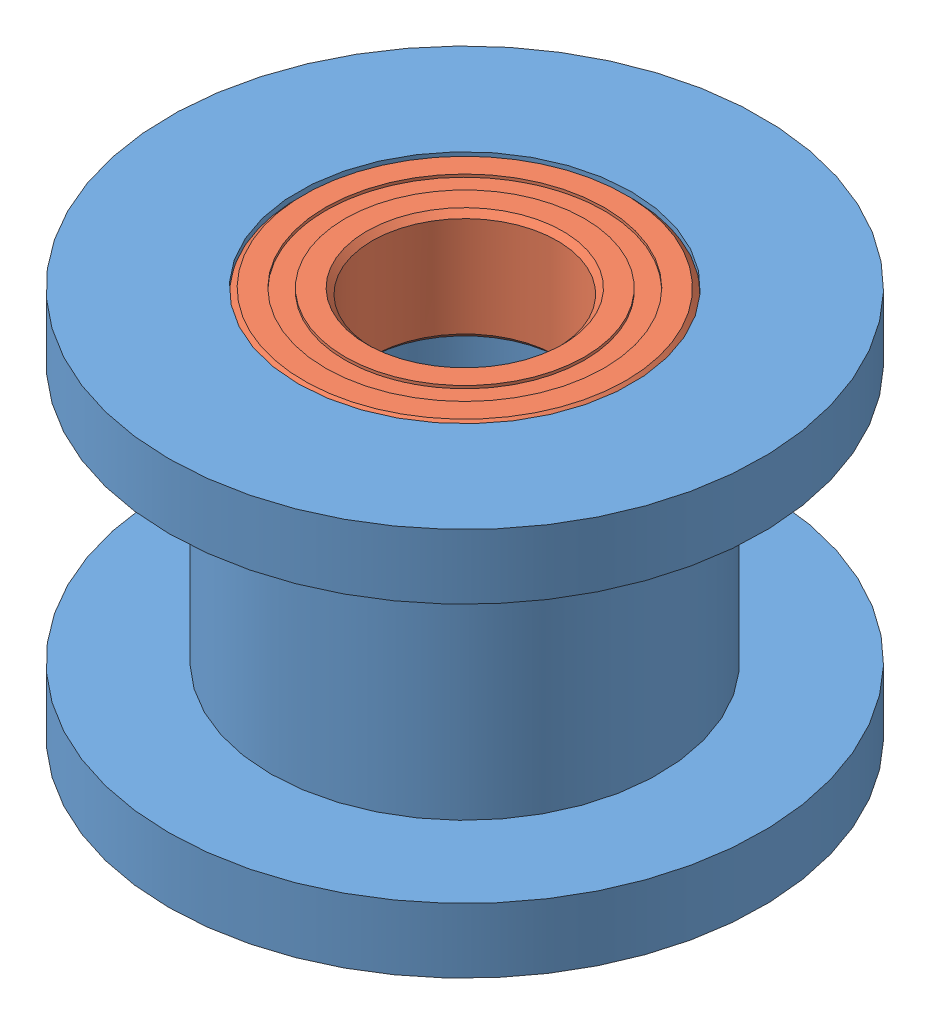
SolidWorks assembly Assem2, configuration Default. Lengths in mm.
Overall size (16 10.5 16).
3 component instances, 2 part files, 5 mates.
Components (placement in the parent):
- Aluminum Idler Pulley-1: Aluminum Idler Pulley [Default] at origin size (16 10.5 16)
- 95-2Z Bearing-1: 95-2Z Bearing [7804K105] at (0 -1.5 0) x (1 0 0) z (0 -1 0) size (9 9 3)
- 95-2Z Bearing-2: 95-2Z Bearing [7804K105] at (0 -9 0) x (1 0 0) z (0 -1 0) size (9 9 3)
Mates (geometry in assembly coordinates):
- Coincident1: coordinate: point of Aluminum Idler Pulley-1; point of assembly
- Concentric1: concentric: cylinder of Aluminum Idler Pulley-1 through (0 0 0) axis (0 1 0) radius 4.5; cylinder of 95-2Z Bearing-1 through (0 -3 0) axis (0 -1 0) radius 4.5
- Coincident2: coincident anti-aligned: plane of Aluminum Idler Pulley-1 through (-3 -3 0) normal (0 1 0); plane of 95-2Z Bearing-1 through (0 -3 4.35) normal (0 -1 0)
- Concentric2: concentric: cylinder of Aluminum Idler Pulley-1 through (0 0 0) axis (0 1 0) radius 4.5; cylinder of 95-2Z Bearing-2 through (0 -10.5 0) axis (0 -1 0) radius 4.5
- Coincident3: coincident anti-aligned: plane of Aluminum Idler Pulley-1 through (-3 -7.5 0) normal (0 -1 0); plane of 95-2Z Bearing-2 through (0 -7.5 4.35) normal (0 1 0)
